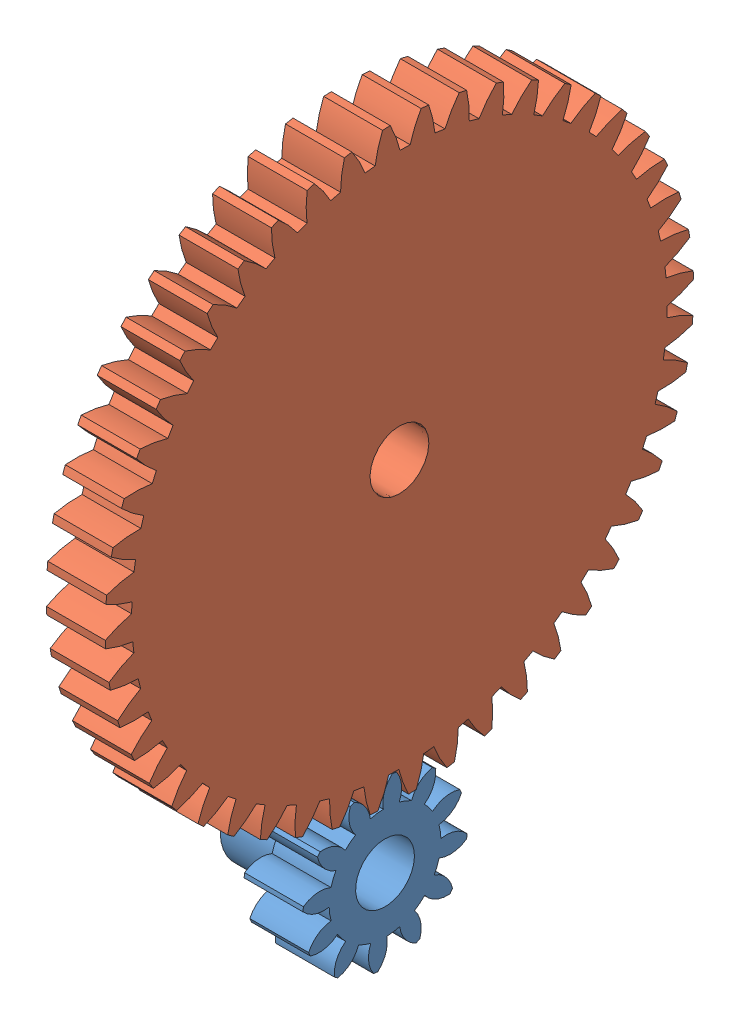
SolidWorks assembly Assem2, configuration Default. Lengths in mm.
Overall size (20 129.64 101.95).
2 component instances, 2 part files, 4 mates.
Components (placement in the parent):
- 12 teeth-1: 12 teeth [Default] at (-120.1547 -25.2381 -59.8409) x (-1 0 0) z (0 -0.622505 0.782616) size (20 27.23 27.23)
- 48 teeth-1: 48 teeth [Default] at (-66.5856 6.5032 41.7152) x (-1 0 0) z (0 -0.021092 -0.999778) size (20 99.86 99.86)
Mates (geometry in assembly coordinates):
- Coincident2: coincident aligned: plane of 12 teeth-1 through (10 -63.84 -0.1012) normal (1 0 0); plane of 48 teeth-1 through (10 -4.3027 -2.5469) normal (1 0 0)
- GearMate1: gear = 4 : 1 mm: cylinder of 48 teeth-1 through (-40.0001 -4.3027 -2.5469) axis (1 0 0) radius 5; cylinder of 12 teeth-1 through (-40.0001 -63.84 -0.1012) axis (1 0 0) radius 5
- Coincident3: coincident anti-aligned: plane of 48 teeth-1 through (0 -4.3027 -2.5469) normal (-1 0 0); plane of assembly through (0 0 0) normal (1 0 0)
- Coincident4: coincident: cylinder of 48 teeth-1 through (-40.0001 -4.3027 -2.5469) axis (1 0 0) radius 5; point of assembly
